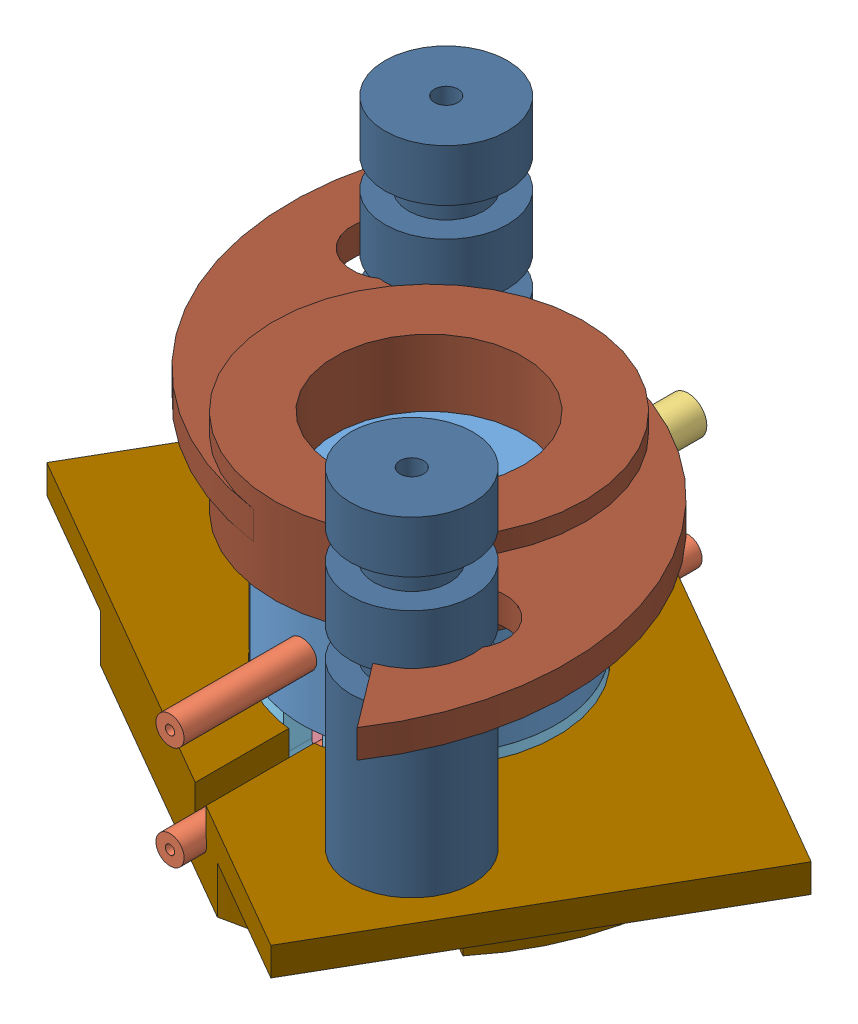
SolidWorks assembly mycroscope clamp 3D + LVB1, configuration Default. Lengths in mm.
Overall size (77.29 43 68.87).
17 component instances, 11 part files, 7 mates.
Components (placement in the parent):
- 3D view live box 1-1: 3D view live box 1 [Assemblata] at (6.7199 -46.9356 0) size (27 23 55)
  - 3Dview-Top-1: 3Dview-Top [Default] at (-2.6946 -4.6013 0) size (27 15 55)
    - Top-1: Top [Default] at origin size (27 15 27)
    - 3x1-1: 3x1 [Default] at (0 6.5 7.5) x (0.999962 0.00877 0) z (0 0 1) size (3 3 20)
    - 4x2-1: 4x2 [Default] at (0 8 -27.5) size (4 4 20)
  - 3Dview-Inner bottom-1: 3Dview-Inner bottom [Default] at (-2.6946 -11.6013 0) x (0 0 -1) z (1 0 0) size (55 6.7 21)
    - Inner bottom-1: Inner bottom [Default] at origin size (21 6.7 21)
    - 3x1-2: 3x1 [Default] at (-7.5 2.5 0) x (0 0.981723 0.190315) z (-1 0 0) size (3 3 20)
    - 3x1-4: 3x1 [Default] at (27.5 2.5 0) x (0 -0.991525 0.129918) z (-1 0 0) size (3 3 20)
  - Bottom-1: Bottom [Default] at (-2.6946 -12.6013 0) x (0 0 -1) z (1 0 0) size (27 8 27)
  - Inner up-1: Inner up [Default] at (-2.6946 -6.6013 0) size (21 4.9 21)
  - glass bottom-1: glass bottom [Default] at (-2.6946 -11.6013 0) size (21 0.3 21)
  - Membrane-1: Membrane [Default] at (-2.6946 -6.6013 0) size (19 0.1 19)
- mycroscope clamp base-1: mycroscope clamp base [Default] at (4.0253 -60.5369 0) x (0.866025 0 0.5) z (-0.5 0 0.866025) size (65 8 42)
- mycroscope clamp colonna-1: mycroscope clamp colonna [Default] at (-12.1415 -52.5369 -17.9942) size (13 37 13)
- mycroscope clamp colonna-2: mycroscope clamp colonna [Default] at (20.1921 -52.5369 17.9942) size (13 37 13)
- mycroscope clamp ali LVB1-2: mycroscope clamp ali LVB1 [Default] at (4.0253 -34.4369 0) x (0.990162 0 0.139923) z (-0.139923 0 0.990162) size (60.98 9.1 54.76)
Mates (geometry in assembly coordinates):
- Concentrico1: concentric anti-aligned: circle of 3D view live box 1-1/Bottom-1; circle of mycroscope clamp base-1
- Coincidente1: coincident anti-aligned: plane of 3D view live box 1-1/Bottom-1 through (4.0253 -59.5369 0) normal (0 -1 0); plane of mycroscope clamp base-1 through (4.0253 -59.5369 0) normal (0 1 0)
- Parallelo1: parallel aligned: cylinder of 3D view live box 1-1/3Dview-Inner bottom-1/3x1-2 through (4.0253 -56.0369 27.5) axis (0 0 -1) radius 1.5; cylinder of mycroscope clamp base-1 through (4.0253 -55.5369 0) axis (0 0 -1) radius 1.35
- Coincidente2: coincident anti-aligned: circle of mycroscope clamp base-1; circle of mycroscope clamp colonna-1
- Coincidente4: coincident anti-aligned: circle of mycroscope clamp base-1; circle of mycroscope clamp colonna-2
- Concentrico13: concentric aligned: circle of 3D view live box 1-1/3Dview-Top-1/Top-1; circle of mycroscope clamp ali LVB1-2
- Coincidente5: coincident anti-aligned: plane of 3D view live box 1-1/3Dview-Top-1/Top-1 through (4.0253 -36.5369 0) normal (0 1 0); plane of mycroscope clamp ali LVB1-2 through (4.0253 -36.5369 0) normal (0 -1 0)
